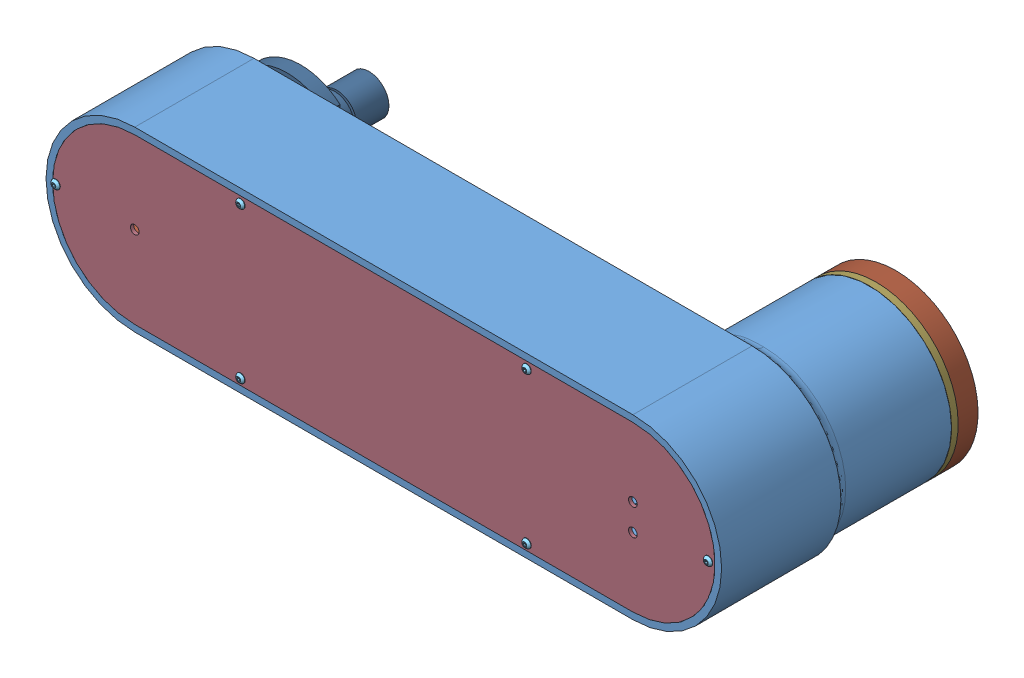
SolidWorks assembly Motor Link, configuration Default. Lengths in mm.
Overall size (327.1 91.59 127.3).
63 component instances, 27 part files, 112 mates.
Components (placement in the parent):
- Motor Link Frame-1: Motor Link Frame [Default] at (-50.4139 21.6178 -80.676) size (323.85 85.09 113.36)
- EC60 Motor-1: EC60 Motor [Default] at (-50.4139 21.6178 -74.326) x (0 0 1) z (0.889011 0.457885 0) size (61.3 68 68)
- Magnet Encoders E3-X-750-X-H-D-X-1: Magnet Encoders E3-X-750-X-H-D-X [Default] at (188.3461 21.6178 -70.897) x (0 -1 0) z (-1 0 0) size (55.98 16.26 66.52)
- EM237 Magnet-1: EM237 Magnet [Default] at (188.3461 21.6178 -135.4915) x (0.985716 -0.168418 0) z (0.168418 0.985716 0) size (60.08 25.02 60.08)
- magnet holder-1: magnet holder [Default] at (191.8291 19.6509 -122.982) x (0.870755 -0.491717 0) z (-0.491717 -0.870755 0) size (50.8 63.9 50.6)
- PCB_Battery Assembly-3: PCB_Battery Assembly [Default] at (165.0497 -0.0136 45.5715) x (1 0 0) z (0 1 0) size (117.17 24.87 77.22)
  - Battery Holder - keystone-PN1043-1: Battery Holder - keystone-PN1043 [Default] at (-125.3925 103.3982 18.9155) x (1 0 0) z (0 0 -1) size (20.65 18.93 77.14)
  - Battery PCB-1: Battery PCB [Default] at (-148.3186 115.135 -16.9005) x (1 0 0) z (0 -1 0) size (117.17 77.06 1.59)
  - battery_6612-1: battery_6612 [Default] at (-117.0385 104.4035 -11.3639) x (-0.413992 0.91028 0) z (0.91028 0.413992 0) size (18.3 65.05 18.3)
  - battery_6612-2: battery_6612 [Default] at (-137.9935 104.4035 54.6265) x (-0.916106 0.400937 0) z (-0.400937 -0.916106 0) size (18.3 65.05 18.3)
  - Battery Holder - keystone-PN1043-2: Battery Holder - keystone-PN1043 [Default] at (-129.6396 103.3982 24.3471) x (-1 0 0) z (0 0 1) size (20.65 18.93 77.14)
  - Battery Holder - keystone-PN1043-3: Battery Holder - keystone-PN1043 [Default] at (-104.4375 103.3982 18.9155) x (1 0 0) z (0 0 -1) size (20.65 18.93 77.14)
  - battery_6612-3: battery_6612 [Default] at (-96.0835 104.4035 -10.3735) x (1 0 0) z (0 -1 0) size (18.3 65.05 18.3)
  - Battery Holder - keystone-PN1043-4: Battery Holder - keystone-PN1043 [Default] at (-83.4825 103.3982 18.9155) x (1 0 0) z (0 0 -1) size (20.65 18.93 77.14)
  - Battery Holder - keystone-PN1043-5: Battery Holder - keystone-PN1043 [Default] at (-45.8196 103.3982 24.3471) x (-1 0 0) z (0 0 1) size (20.65 18.93 77.14)
  - battery_6612-4: battery_6612 [Default] at (-75.1285 104.4035 -11.3639) x (-0.923728 -0.383049 0) z (-0.383049 0.923728 0) size (18.3 65.05 18.3)
  - battery_6612-5: battery_6612 [Default] at (-54.1735 104.4035 54.6265) x (-1 0 0) z (0 -1 0) size (18.3 65.05 18.3)
- carrier_shaft-1: carrier_shaft [Default] at (-50.4139 39.1178 -75.596) x (-0.887515 0.46078 0) z (-0.46078 -0.887515 0) size (9 25.81 9)
- carrier_shaft-2: carrier_shaft [Default] at (-50.4139 4.1178 -75.596) x (-0.791269 0.611469 0) z (-0.611469 -0.791269 0) size (9 25.81 9)
- Shaft_Carrier_Combined-1: Shaft_Carrier_Combined [Default] at (-50.4139 21.6178 -103.1385) x (0 1 0) z (-1 0 0) size (57.15 55.17 57.15)
- Delrin_Ring-1: Delrin_Ring [Default] at (188.3461 21.6178 -149.5885) x (1 0 0) z (0 -1 0) size (78.74 9.53 78.74)
- Neoprene Ring-1: Neoprene Ring [Default] at (188.3461 21.6178 -140.0635) x (1 0 0) z (0 -1 0) size (78.74 3.17 78.74)
- Motor Link Acrylic Cover-1: Motor Link Acrylic Cover [Default] at (188.3461 21.6178 -25.1135) x (-1 0 0) z (0 1 0) size (317.5 1.59 78.74) (hidden)
- Slip Ring M322M1-0600-1: Slip Ring M322M1-0600 [Default] at (188.3461 21.6178 -50.305) x (-0.866025 -0.5 0) z (0 0 -1) size (44 44 48)
- bearing_8mmID_mcmaster_7804K115-1: bearing_8mmID_mcmaster_7804K115 [7804K115] at (-50.4139 39.1178 -78.926) x (-0.923728 -0.383049 0) z (0 0 -1) size (12 12 3.5)
- bearing_8mmID_mcmaster_7804K115-2: bearing_8mmID_mcmaster_7804K115 [7804K115] at (-50.4139 4.1178 -78.926) x (0.919429 -0.393256 0) z (0 0 -1) size (12 12 3.5)
- Bearing-I8mmO16mm-1: Bearing-I8mmO16mm [7804K117] at (-50.4139 4.1178 -99.051) x (0.999987 0.005155 0) z (0 0 1) size (16 16 5)
- Bearing-I8mmO16mm-2: Bearing-I8mmO16mm [7804K117] at (-50.4139 39.1178 -99.051) x (0.862389 -0.506247 0) z (0 0 -1) size (16 16 5)
- Bearing - .750-1: Bearing - .750 [3760T241] at (188.3461 21.6178 -86.2323) x (-0.324728 0.945808 0) z (0 0 1) size (41.27 41.27 11.11)
- Bearing - .750-2: Bearing - .750 [3760T241] at (188.3461 21.6178 -97.3448) x (0.923728 0.383049 0) z (0 0 -1) size (41.27 41.27 11.11)
- 10-32 Button Cap Thread Locking Screw-1: 10-32 Button Cap Thread Locking Screw [92360A244] at (-26.9189 13.9978 -89.5914) x (-0.890787 -0.45442 0) z (0 0 -1) size (9.17 9.17 12.51)
- 10-32 Button Cap Thread Locking Screw-2: 10-32 Button Cap Thread Locking Screw [92360A244] at (-73.9089 13.9978 -89.5914) x (-0.923728 -0.383049 0) z (0 0 -1) size (9.17 9.17 12.51)
- 10-32 Button Cap Thread Locking Screw-3: 10-32 Button Cap Thread Locking Screw [92360A244] at (-26.9189 29.2378 -89.5914) x (-0.923728 -0.383049 0) z (0 0 -1) size (9.17 9.17 12.51)
- 10-32 Button Cap Thread Locking Screw-4: 10-32 Button Cap Thread Locking Screw [92360A244] at (-73.9089 29.2378 -89.5914) x (-0.923728 -0.383049 0) z (0 0 -1) size (9.17 9.17 12.51)
- 1.625 Bore Internal Retaining Ring-1: 1.625 Bore Internal Retaining Ring [99142A560] at (188.3461 21.6178 -103.0534) x (1 0 0) z (0 -1 0) size (45.82 1.57 43.68)
- M8_L16mm Screws-1: M8_L16mm Screws [91760A423] at (188.3461 21.6178 -132.632) x (0.923728 0.383049 0) z (0 0 -1) size (13 13 24.67)
- .75 Bore External Retaining Ring-1: .75 Bore External Retaining Ring [97633A250] at (188.3461 21.6178 -80.1426) x (0 0 1) z (0.923728 0.383049 0) size (1.07 23.39 21.18)
- Dowel Pin - .0625-1: Dowel Pin - .0625 [97395A414] at (188.3461 57.8128 -133.7135) x (0 0 1) z (-1 0 0) size (19.05 1.59 1.59)
- Dowel Pin - .0625-2: Dowel Pin - .0625 [97395A414] at (224.5411 21.6178 -133.7135) x (0 0 1) z (-1 0 0) size (19.05 1.59 1.59)
- Dowel Pin - .0625-3: Dowel Pin - .0625 [97395A414] at (188.3461 -14.5772 -133.7135) x (0 0 1) z (-1 0 0) size (19.05 1.59 1.59)
- Dowel Pin - .0625-4: Dowel Pin - .0625 [97395A414] at (152.1511 21.6178 -133.7135) x (0 0 1) z (-1 0 0) size (19.05 1.59 1.59)
- 2-56 Screw-1: 2-56 Screw [98164A427] at (-88.1964 21.6178 -22.3576) size (4.17 4.17 10.95)
- 2-56 Screw-2: 2-56 Screw [98164A427] at (0.3861 57.8128 -22.3576) x (0.033268 -0.999446 0) z (0 0 1) size (4.17 4.17 10.95)
- 2-56 Screw-3: 2-56 Screw [98164A427] at (0.3861 -14.5772 -22.3576) size (4.17 4.17 10.95)
- 2-56 Screw-4: 2-56 Screw [98164A427] at (137.5461 -14.5772 -22.3576) size (4.17 4.17 10.95)
- 2-56 Screw-5: 2-56 Screw [98164A427] at (224.5411 21.6178 -22.3576) size (4.17 4.17 10.95)
- 2-56 Screw-6: 2-56 Screw [98164A427] at (137.5461 57.8128 -22.3576) size (4.17 4.17 10.95)
- M5 Screws-1: M5 Screws [91352A131] at (197.0961 36.7732 -47.555) size (9.5 9.5 13.21)
- M5 Screws-2: M5 Screws [91352A131] at (197.0961 6.4623 -47.555) size (9.5 9.5 13.21)
- M5 Screws-3: M5 Screws [91352A131] at (170.8461 21.6178 -47.555) size (9.5 9.5 13.21)
- M5 Nylon Spacer-1: M5 Nylon Spacer [93657A042] at (198.7861 21.6178 -55.705) size (8 8 6)
- M5 Nylon Spacer-2: M5 Nylon Spacer [93657A042] at (197.0961 6.4623 -55.705) x (-0.923728 -0.383049 0) z (0 0 -1) size (8 8 6)
- M5 Nylon Spacer-3: M5 Nylon Spacer [93657A042] at (197.0961 36.7732 -55.705) size (8 8 6)
- 4-40 Screws-1: 4-40 Screws [92949A108] at (188.3461 -1.3946 -69.3984) size (5.41 5.41 11.35)
- 4-40 Screws-2: 4-40 Screws [92949A108] at (188.3461 44.6302 -69.3984) size (5.41 5.41 11.35)
- 2-56 Screw-7: 2-56 Screw [98164A427] at (13.556 53.7996 -66.8076) size (4.17 4.17 10.95)
- 2-56 Screw-8: 2-56 Screw [98164A427] at (124.3762 53.7996 -66.8076) size (4.17 4.17 10.95)
- 2-56 Screw-9: 2-56 Screw [98164A427] at (124.3762 -10.564 -66.8076) size (4.17 4.17 10.95)
- 2-56 Screw-10: 2-56 Screw [98164A427] at (13.556 -10.564 -66.8076) size (4.17 4.17 10.95)
- #2 Spacer-1: #2 Spacer [94639A188] at (13.556 -10.564 -71.9448) x (0.923728 0.383049 0) z (0 0 -1) size (6.35 6.35 4.76)
- #2 Spacer-2: #2 Spacer [94639A188] at (124.3762 -10.564 -71.9448) x (0.923728 0.383049 0) z (0 0 -1) size (6.35 6.35 4.76)
- #2 Spacer-3: #2 Spacer [94639A188] at (124.3762 53.7996 -71.9448) x (0.923728 0.383049 0) z (0 0 -1) size (6.35 6.35 4.76)
- #2 Spacer-4: #2 Spacer [94639A188] at (13.556 53.7996 -71.9448) x (0.923728 0.383049 0) z (0 0 -1) size (6.35 6.35 4.76)
Mates (geometry in assembly coordinates):
- Coincident2: coincident aligned: line of Motor Link Frame-1 through (-50.4139 21.6178 -80.676) axis (0 0 1); line of EC60 Motor-1 through (-50.4139 21.6178 -95.9581) axis (0 0 1)
- Coincident3: coincident anti-aligned: plane of Motor Link Frame-1 through (-50.4139 21.6178 -74.326) normal (0 0 1); plane of EC60 Motor-1
- Coincident4: coincident: plane of Motor Link Frame-1 through (-50.4139 21.6178 -80.676) normal (0 0 -1); plane of bearing_8mmID_mcmaster_7804K115-1 through (-50.4139 39.1178 -80.676) normal (0 0 -1)
- Coincident5: coincident aligned: line of Motor Link Frame-1 through (-50.4139 39.1178 -80.676) axis (0 0 1); line of bearing_8mmID_mcmaster_7804K115-1 through (-50.4139 39.1178 -77.176) axis (0 0 1)
- Coincident6: coincident: plane of Motor Link Frame-1 through (-50.4139 21.6178 -80.676) normal (0 0 -1); plane of bearing_8mmID_mcmaster_7804K115-2 through (-50.4139 4.1178 -80.676) normal (0 0 -1)
- Coincident7: coincident aligned: line of Motor Link Frame-1 through (-50.4139 4.1178 -80.676) axis (0 0 1); line of bearing_8mmID_mcmaster_7804K115-2 through (-50.4139 4.1178 -77.176) axis (0 0 1)
- Concentric1: concentric: point of Motor Link Frame-1; cylinder of Magnet Encoders E3-X-750-X-H-D-X-1 through (188.3461 21.6178 -64.3438) axis (0 0 1) radius 9.5263
- Coincident11: coincident anti-aligned: plane of Motor Link Frame-1 through (-50.4139 21.6178 -74.326) normal (0 0 1); plane of Magnet Encoders E3-X-750-X-H-D-X-1 through (188.3461 21.6178 -74.326) normal (0 0 -1)
- Perpendicular1: perpendicular: plane of Motor Link Frame-1 through (-50.4139 64.1628 -80.676) normal (0 1 0); plane of Magnet Encoders E3-X-750-X-H-D-X-1 through (155.1229 6.0623 -72.4718) normal (-0.999391 0 0.034899)
- Concentric2: concentric aligned: line of Motor Link Frame-1 through (188.3461 21.6178 -136.8885) axis (0 0 1); cylinder of EM237 Magnet-1 through (188.3461 21.6178 -148.001) axis (0 0 1) radius 30.0419
- Coincident16: coincident anti-aligned: line of Motor Link Frame-1 through (188.3461 21.6178 -136.8885) axis (0 0 1); line of magnet holder-1 through (188.3461 21.6178 -59.086) axis (0 0 -1)
- Coincident26: coincident aligned: line of carrier_shaft-1 through (-50.4139 39.1178 -92.596) axis (0 0 1); line of Motor Link Frame-1 through (-50.4139 39.1178 -80.676) axis (0 0 1)
- Coincident29: coincident aligned: line of Motor Link Frame-1 through (-50.4139 4.1178 -80.676) axis (0 0 1); line of carrier_shaft-2 through (-50.4139 4.1178 -92.596) axis (0 0 1)
- Coincident37: coincident aligned: line of Motor Link Frame-1 through (-50.4139 21.6178 -80.676) axis (0 0 1); line of Shaft_Carrier_Combined-1 through (-50.4139 21.6178 -135.841) axis (0 0 1)
- Coincident38: coincident aligned: line of Motor Link Frame-1 through (-50.4139 4.1178 -80.676) axis (0 0 1); line of Shaft_Carrier_Combined-1 through (-50.4139 4.1178 -101.551) axis (0 0 1)
- Coincident39: coincident aligned: line of Motor Link Frame-1 through (-50.4139 39.1178 -80.676) axis (0 0 1); line of Shaft_Carrier_Combined-1 through (-50.4139 39.1178 -101.551) axis (0 0 1)
- Coincident41: coincident anti-aligned: plane of Motor Link Frame-1 through (-50.4139 21.6178 -80.676) normal (0 0 -1); plane of Shaft_Carrier_Combined-1
- Coincident42: coincident anti-aligned: line of Shaft_Carrier_Combined-1 through (-50.4139 4.1178 -101.551) axis (0 0 1); line of Bearing-I8mmO16mm-1 through (-50.4139 4.1178 -101.551) axis (0 0 -1)
- Coincident44: coincident aligned: line of Shaft_Carrier_Combined-1 through (-50.4139 39.1178 -101.551) axis (0 0 1); line of Bearing-I8mmO16mm-2 through (-50.4139 39.1178 -96.551) axis (0 0 1)
- Coincident46: coincident anti-aligned: plane of Motor Link Frame-1 through (-50.4139 39.1178 -75.596) normal (0 0 -1); plane of carrier_shaft-1 through (-50.4139 39.1178 -75.596) normal (0 0 1)
- Coincident47: coincident anti-aligned: plane of Motor Link Frame-1 through (-50.4139 4.1178 -75.596) normal (0 0 -1); plane of carrier_shaft-2 through (-50.4139 4.1178 -75.596) normal (0 0 1)
- Coincident51: coincident anti-aligned: plane of Shaft_Carrier_Combined-1 through (-50.4139 4.1178 -101.551) normal (0 0 1); plane of Bearing-I8mmO16mm-1 through (-50.4538 11.8676 -101.551) normal (0 0 -1)
- Coincident52: coincident anti-aligned: plane of Shaft_Carrier_Combined-1 through (-50.4139 39.1178 -101.551) normal (0 0 1); plane of Bearing-I8mmO16mm-2 through (-54.3373 32.4342 -101.551) normal (0 0 -1)
- Coincident53: coincident aligned: line of Motor Link Frame-1 through (-26.9189 13.9978 -76.866) axis (0 0 -1); line of 10-32 Button Cap Thread Locking Screw-1 through (-26.9189 13.9978 -77.501) axis (0 0 -1)
- Coincident54: coincident anti-aligned: plane of Shaft_Carrier_Combined-1 through (-50.4139 21.6178 -87.026) normal (0 0 -1); plane of 10-32 Button Cap Thread Locking Screw-1 through (-24.8355 9.9138 -87.026) normal (0 0 1)
- Coincident55: coincident anti-aligned: plane of Shaft_Carrier_Combined-1 through (-50.4139 21.6178 -87.026) normal (0 0 -1); plane of 10-32 Button Cap Thread Locking Screw-3 through (-25.1627 25.0027 -87.026) normal (0 0 1)
- Coincident56: coincident aligned: line of Motor Link Frame-1 through (-26.9189 29.2378 -76.866) axis (0 0 -1); line of 10-32 Button Cap Thread Locking Screw-3 through (-26.9189 29.2378 -77.501) axis (0 0 -1)
- Coincident57: coincident aligned: line of Motor Link Frame-1 through (-73.9089 13.9978 -76.866) axis (0 0 -1); line of 10-32 Button Cap Thread Locking Screw-2 through (-73.9089 13.9978 -77.501) axis (0 0 -1)
- Coincident58: coincident anti-aligned: plane of Shaft_Carrier_Combined-1 through (-50.4139 21.6178 -87.026) normal (0 0 -1); plane of 10-32 Button Cap Thread Locking Screw-2 through (-72.1527 9.7627 -87.026) normal (0 0 1)
- Coincident59: coincident aligned: line of Motor Link Frame-1 through (-73.9089 29.2378 -76.866) axis (0 0 -1); line of 10-32 Button Cap Thread Locking Screw-4 through (-73.9089 29.2378 -77.501) axis (0 0 -1)
- Coincident60: coincident anti-aligned: plane of Shaft_Carrier_Combined-1 through (-50.4139 21.6178 -87.026) normal (0 0 -1); plane of 10-32 Button Cap Thread Locking Screw-4 through (-72.1527 25.0027 -87.026) normal (0 0 1)
- Coincident61: coincident anti-aligned: line of Motor Link Frame-1 through (188.3461 21.6178 -136.8885) axis (0 0 1); line of Bearing - .750-1 through (188.3461 21.6178 -91.7885) axis (0 0 -1)
- Coincident62: coincident anti-aligned: plane of Motor Link Frame-1 through (188.3461 21.6178 -80.676) normal (0 0 -1); plane of Bearing - .750-1 through (169.3525 15.0966 -80.676) normal (0 0 1)
- Concentric6: concentric aligned: line of Motor Link Frame-1 through (188.3461 21.6178 -136.8885) axis (0 0 1); cylinder of 1.625 Bore Internal Retaining Ring-1 through (188.3461 21.6178 -104.6282) axis (0 0 1) radius 22.9108
- Concentric8: concentric anti-aligned: line of Motor Link Frame-1 through (188.3461 21.6178 -136.8885) axis (0 0 1); cylinder of Bearing - .750-2 through (188.3461 21.6178 -102.901) axis (0 0 -1) radius 9.525
- Coincident68: coincident anti-aligned: plane of Motor Link Frame-1 through (188.3461 21.6178 -104.6282) normal (0 0 1); plane of 1.625 Bore Internal Retaining Ring-1 through (199.3349 4.8737 -104.6282) normal (0 0 -1)
- Coincident69: coincident anti-aligned: plane of Bearing - .750-1 through (169.3525 15.0966 -91.7885) normal (0 0 -1); plane of Bearing - .750-2 through (196.0385 3.0676 -91.7885) normal (0 0 1)
- Coincident71: coincident anti-aligned: plane of magnet holder-1 through (199.4047 15.3729 -102.901) normal (0 0 1); plane of Bearing - .750-2 through (193.6151 8.9115 -102.901) normal (0 0 -1)
- Coincident72: coincident anti-aligned: plane of EM237 Magnet-1 through (188.3461 21.6178 -122.982) normal (0 0 1); plane of magnet holder-1 through (191.8291 19.6509 -122.982) normal (0 0 -1)
- Concentric9: concentric aligned: line of magnet holder-1 through (188.3461 21.6178 -59.086) axis (0 0 -1); cylinder of M8_L16mm Screws-1 through (188.3461 21.6178 -108.632) axis (0 0 -1) radius 6.5
- Coincident74: coincident anti-aligned: plane of magnet holder-1 through (194.221 18.3002 -116.632) normal (0 0 1); plane of M8_L16mm Screws-1 through (188.3461 21.6178 -116.632) normal (0 0 -1)
- Concentric10: concentric aligned: line of magnet holder-1 through (188.3461 21.6178 -59.086) axis (0 0 -1); cylinder of .75 Bore External Retaining Ring-1 through (188.3461 21.6178 -79.6092) axis (0 0 -1) radius 8.8011
- Coincident77: coincident anti-aligned: plane of magnet holder-1 through (188.3461 21.6178 -80.676) normal (0 0 1); plane of .75 Bore External Retaining Ring-1 through (188.3461 21.6178 -80.676) normal (0 0 -1)
- Coincident78: coincident anti-aligned: plane of Motor Link Frame-1 through (188.3461 21.6178 -136.8885) normal (0 0 -1); plane of Neoprene Ring-1 through (188.3461 21.6178 -136.8885) normal (0 0 1)
- Concentric11: concentric anti-aligned: line of Motor Link Frame-1 through (188.3461 21.6178 -136.8885) axis (0 0 1); cylinder of Neoprene Ring-1 through (188.3461 21.6178 -136.8885) axis (0 0 -1) radius 33.02
- Concentric12: concentric anti-aligned: line of Motor Link Frame-1 through (188.3461 21.6178 -136.8885) axis (0 0 1); cylinder of Delrin_Ring-1 through (188.3461 21.6178 -140.0635) axis (0 0 -1) radius 33.02
- Coincident81: coincident anti-aligned: plane of Delrin_Ring-1 through (188.3461 21.6178 -140.0635) normal (0 0 1); plane of Neoprene Ring-1 through (188.3461 21.6178 -140.0635) normal (0 0 -1)
- Concentric13: concentric aligned: cylinder of Motor Link Frame-1 through (224.5411 21.6178 -124.1885) axis (0 0 -1) radius 0.7937; cylinder of Neoprene Ring-1 through (224.5411 21.6178 -136.8885) axis (0 0 -1) radius 0.7937
- Concentric14: concentric aligned: cylinder of Motor Link Frame-1 through (224.5411 21.6178 -124.1885) axis (0 0 -1) radius 0.7937; cylinder of Delrin_Ring-1 through (224.5411 21.6178 -140.0635) axis (0 0 -1) radius 0.7937
- Concentric15: concentric anti-aligned: cylinder of Motor Link Frame-1 through (224.5411 21.6178 -124.1885) axis (0 0 -1) radius 0.7937; cylinder of Dowel Pin - .0625-2 through (224.5411 21.6178 -143.2385) axis (0 0 1) radius 0.7937
- Coincident82: coincident anti-aligned: plane of Motor Link Frame-1 through (224.5411 21.6178 -124.1885) normal (0 0 -1); plane of Dowel Pin - .0625-2 through (224.5411 21.6178 -124.1885) normal (0 0 1)
- Concentric16: concentric anti-aligned: cylinder of Motor Link Frame-1 through (188.3461 57.8128 -124.1885) axis (0 0 -1) radius 0.7937; cylinder of Dowel Pin - .0625-1 through (188.3461 57.8128 -143.2385) axis (0 0 1) radius 0.7937
- Coincident83: coincident anti-aligned: plane of Motor Link Frame-1 through (188.3461 57.8128 -124.1885) normal (0 0 -1); plane of Dowel Pin - .0625-1 through (188.3461 57.8128 -124.1885) normal (0 0 1)
- Concentric17: concentric anti-aligned: cylinder of Motor Link Frame-1 through (152.1511 21.6178 -124.1885) axis (0 0 -1) radius 0.7937; cylinder of Dowel Pin - .0625-4 through (152.1511 21.6178 -143.2385) axis (0 0 1) radius 0.7937
- Coincident84: coincident anti-aligned: plane of Motor Link Frame-1 through (152.1511 21.6178 -124.1885) normal (0 0 -1); plane of Dowel Pin - .0625-4 through (152.1511 21.6178 -124.1885) normal (0 0 1)
- Concentric18: concentric anti-aligned: cylinder of Motor Link Frame-1 through (188.3461 -14.5772 -124.1885) axis (0 0 -1) radius 0.7937; cylinder of Dowel Pin - .0625-3 through (188.3461 -14.5772 -143.2385) axis (0 0 1) radius 0.7937
- Coincident85: coincident anti-aligned: plane of Motor Link Frame-1 through (188.3461 -14.5772 -124.1885) normal (0 0 -1); plane of Dowel Pin - .0625-3 through (188.3461 -14.5772 -124.1885) normal (0 0 1)
- Coincident86: coincident anti-aligned: plane of Motor Link Acrylic Cover-1 through (188.3461 21.6178 -25.1135) normal (0 0 -1); plane of Motor Link Frame-1 through (-50.4139 21.6178 -25.1135) normal (0 0 1)
- Concentric26: concentric anti-aligned: cylinder of Motor Link Frame-1 through (-88.1964 21.6178 -25.1135) axis (0 0 1) radius 0.889; cylinder of Motor Link Acrylic Cover-1 through (-88.1964 21.6178 -23.526) axis (0 0 -1) radius 1.0922
- Concentric27: concentric anti-aligned: cylinder of Motor Link Frame-1 through (224.5411 21.6178 -25.1135) axis (0 0 1) radius 0.889; cylinder of Motor Link Acrylic Cover-1 through (224.5411 21.6178 -23.526) axis (0 0 -1) radius 1.0922
- Concentric28: concentric anti-aligned: cylinder of Motor Link Acrylic Cover-1 through (-88.1964 21.6178 -23.526) axis (0 0 -1) radius 1.0922; line of 2-56 Screw-1 through (-88.1964 21.6178 -33.051) axis (0 0 1)
- Coincident88: coincident anti-aligned: plane of Motor Link Acrylic Cover-1 through (188.3461 21.6178 -23.526) normal (0 0 1); plane of 2-56 Screw-1 through (-88.1964 19.535 -23.526) normal (0 0 -1)
- Concentric29: concentric anti-aligned: cylinder of Motor Link Acrylic Cover-1 through (0.3861 57.8128 -23.526) axis (0 0 -1) radius 1.0922; line of 2-56 Screw-2 through (0.3861 57.8128 -33.051) axis (0 0 1)
- Coincident90: coincident anti-aligned: plane of Motor Link Acrylic Cover-1 through (188.3461 21.6178 -23.526) normal (0 0 1); plane of 2-56 Screw-2 through (-1.6955 57.7435 -23.526) normal (0 0 -1)
- Concentric30: concentric anti-aligned: cylinder of Motor Link Acrylic Cover-1 through (0.3861 -14.5772 -23.526) axis (0 0 -1) radius 1.0922; line of 2-56 Screw-3 through (0.3861 -14.5772 -33.051) axis (0 0 1)
- Coincident92: coincident anti-aligned: plane of Motor Link Acrylic Cover-1 through (188.3461 21.6178 -23.526) normal (0 0 1); plane of 2-56 Screw-3 through (0.3861 -16.66 -23.526) normal (0 0 -1)
- Concentric31: concentric anti-aligned: cylinder of Motor Link Acrylic Cover-1 through (137.5461 -14.5772 -23.526) axis (0 0 -1) radius 1.0922; line of 2-56 Screw-4 through (137.5461 -14.5772 -33.051) axis (0 0 1)
- Coincident94: coincident anti-aligned: plane of Motor Link Acrylic Cover-1 through (188.3461 21.6178 -23.526) normal (0 0 1); plane of 2-56 Screw-4 through (137.5461 -16.66 -23.526) normal (0 0 -1)
- Concentric32: concentric anti-aligned: cylinder of Motor Link Acrylic Cover-1 through (137.5461 57.8128 -23.526) axis (0 0 -1) radius 1.0922; line of 2-56 Screw-6 through (137.5461 57.8128 -33.051) axis (0 0 1)
- Coincident96: coincident anti-aligned: plane of Motor Link Acrylic Cover-1 through (188.3461 21.6178 -23.526) normal (0 0 1); plane of 2-56 Screw-6 through (137.5461 55.73 -23.526) normal (0 0 -1)
- Concentric33: concentric anti-aligned: cylinder of Motor Link Acrylic Cover-1 through (224.5411 21.6178 -23.526) axis (0 0 -1) radius 1.0922; line of 2-56 Screw-5 through (224.5411 21.6178 -33.051) axis (0 0 1)
- Coincident98: coincident anti-aligned: plane of Motor Link Acrylic Cover-1 through (188.3461 21.6178 -23.526) normal (0 0 1); plane of 2-56 Screw-5 through (224.5411 19.535 -23.526) normal (0 0 -1)
- Distance2: distance = 6 mm anti-aligned: plane of Slip Ring M322M1-0600-1 through (169.2936 10.6178 -52.705) normal (0 0 -1); plane of Magnet Encoders E3-X-750-X-H-D-X-1 through (188.3461 21.6178 -58.705) normal (0 0 1)
- Concentric34: concentric aligned: line of Motor Link Frame-1 through (188.3461 21.6178 -136.8885) axis (0 0 1); cylinder of Slip Ring M322M1-0600-1 through (188.3461 21.6178 -66.705) axis (0 0 1) radius 3.8
- Concentric35: concentric aligned: cylinder of Slip Ring M322M1-0600-1 through (170.8461 21.6178 -50.305) axis (0 0 1) radius 2.75; cylinder of Magnet Encoders E3-X-750-X-H-D-X-1 through (170.8461 21.6178 -58.705) axis (0 0 1) radius 2.1
- Concentric36: concentric aligned: cylinder of Magnet Encoders E3-X-750-X-H-D-X-1 through (197.0961 6.4623 -58.705) axis (0 0 1) radius 2.1; cylinder of Slip Ring M322M1-0600-1 through (197.0961 6.4623 -50.305) axis (0 0 1) radius 2.75
- Concentric37: concentric aligned: cylinder of Magnet Encoders E3-X-750-X-H-D-X-1 through (197.0961 36.7732 -58.705) axis (0 0 1) radius 2.1; cylinder of Slip Ring M322M1-0600-1 through (197.0961 36.7732 -50.305) axis (0 0 1) radius 2.75
- Concentric38: concentric aligned: cylinder of Slip Ring M322M1-0600-1 through (197.0961 36.7732 -50.305) axis (0 0 1) radius 2.75; line of M5 Screws-1 through (197.0961 36.7732 -60.305) axis (0 0 1)
- Coincident102: coincident anti-aligned: plane of Slip Ring M322M1-0600-1 through (188.3461 21.6178 -50.305) normal (0 0 1); plane of M5 Screws-1 through (197.0961 32.0232 -50.305) normal (0 0 -1)
- Concentric39: concentric aligned: cylinder of Slip Ring M322M1-0600-1 through (197.0961 6.4623 -50.305) axis (0 0 1) radius 2.75; line of M5 Screws-2 through (197.0961 6.4623 -60.305) axis (0 0 1)
- Coincident104: coincident anti-aligned: plane of Slip Ring M322M1-0600-1 through (188.3461 21.6178 -50.305) normal (0 0 1); plane of M5 Screws-2 through (197.0961 1.7123 -50.305) normal (0 0 -1)
- Concentric40: concentric aligned: cylinder of Slip Ring M322M1-0600-1 through (170.8461 21.6178 -50.305) axis (0 0 1) radius 2.75; line of M5 Screws-3 through (170.8461 21.6178 -60.305) axis (0 0 1)
- Coincident106: coincident anti-aligned: plane of Slip Ring M322M1-0600-1 through (188.3461 21.6178 -50.305) normal (0 0 1); plane of M5 Screws-3 through (170.8461 16.8678 -50.305) normal (0 0 -1)
- Coincident107: coincident anti-aligned: plane of Magnet Encoders E3-X-750-X-H-D-X-1 through (188.3461 21.6178 -58.705) normal (0 0 1); plane of M5 Nylon Spacer-1 through (198.7861 21.6178 -58.705) normal (0 0 -1)
- Concentric42: concentric aligned: cylinder of Slip Ring M322M1-0600-1 through (197.0961 6.4623 -50.305) axis (0 0 1) radius 2.75; cylinder of M5 Nylon Spacer-2 through (197.0961 6.4623 -58.705) axis (0 0 1) radius 2.65
- Coincident108: coincident anti-aligned: plane of Magnet Encoders E3-X-750-X-H-D-X-1 through (188.3461 21.6178 -58.705) normal (0 0 1); plane of M5 Nylon Spacer-2 through (197.0961 6.4623 -58.705) normal (0 0 -1)
- Concentric43: concentric anti-aligned: cylinder of Slip Ring M322M1-0600-1 through (197.0961 36.7732 -50.305) axis (0 0 1) radius 2.75; cylinder of M5 Nylon Spacer-3 through (197.0961 36.7732 -52.705) axis (0 0 -1) radius 2.65
- Coincident109: coincident anti-aligned: plane of Slip Ring M322M1-0600-1 through (169.2936 10.6178 -52.705) normal (0 0 -1); plane of M5 Nylon Spacer-3 through (197.0961 36.7732 -52.705) normal (0 0 1)
- Concentric48: concentric: cylinder of Motor Link Frame-1 through (-71.9139 21.6178 -80.676) axis (0 0 -1) radius 4; cylinder of EC60 Motor-1 through (-71.9139 21.6178 -74.326) axis (0 0 -1) radius 1.65
- Concentric49: concentric anti-aligned: cylinder of Magnet Encoders E3-X-750-X-H-D-X-1 through (188.3461 -1.3946 -70.897) axis (0 0 -1) radius 1.4351; line of 4-40 Screws-1 through (188.3461 -1.3946 -80.422) axis (0 0 1)
- Coincident115: coincident anti-aligned: plane of Magnet Encoders E3-X-750-X-H-D-X-1 through (188.3461 21.6178 -70.897) normal (0 0 1); plane of 4-40 Screws-1 through (188.3461 -4.0997 -70.897) normal (0 0 -1)
- Concentric50: concentric anti-aligned: cylinder of Magnet Encoders E3-X-750-X-H-D-X-1 through (188.3461 44.6302 -70.897) axis (0 0 -1) radius 1.4351; line of 4-40 Screws-2 through (188.3461 44.6302 -80.422) axis (0 0 1)
- Coincident117: coincident anti-aligned: plane of Magnet Encoders E3-X-750-X-H-D-X-1 through (188.3461 21.6178 -70.897) normal (0 0 1); plane of 4-40 Screws-2 through (188.3461 41.9251 -70.897) normal (0 0 -1)
- Concentric51: concentric anti-aligned: cylinder of PCB_Battery Assembly-3/Battery PCB-1 through (13.556 53.7996 -67.976) axis (0 0 -1) radius 1.0922; cylinder of 2-56 Screw-7 through (13.556 53.7996 -66.8076) axis (0 0 1) radius 2.0828
- Coincident118: coincident anti-aligned: plane of PCB_Battery Assembly-3/Battery PCB-1 through (16.731 -16.914 -67.976) normal (0 0 1); plane of 2-56 Screw-7 through (13.556 51.7168 -67.976) normal (0 0 -1)
- Concentric52: concentric anti-aligned: cylinder of PCB_Battery Assembly-3/Battery PCB-1 through (13.556 -10.564 -67.976) axis (0 0 -1) radius 1.0922; cylinder of 2-56 Screw-10 through (13.556 -10.564 -66.8076) axis (0 0 1) radius 2.0828
- Coincident119: coincident anti-aligned: plane of PCB_Battery Assembly-3/Battery PCB-1 through (16.731 -16.914 -67.976) normal (0 0 1); plane of 2-56 Screw-10 through (13.556 -12.6468 -67.976) normal (0 0 -1)
- Concentric53: concentric anti-aligned: cylinder of PCB_Battery Assembly-3/Battery PCB-1 through (124.3762 53.7996 -67.976) axis (0 0 -1) radius 1.0922; cylinder of 2-56 Screw-8 through (124.3762 53.7996 -66.8076) axis (0 0 1) radius 2.0828
- Coincident120: coincident anti-aligned: plane of PCB_Battery Assembly-3/Battery PCB-1 through (16.731 -16.914 -67.976) normal (0 0 1); plane of 2-56 Screw-8 through (124.3762 51.7168 -67.976) normal (0 0 -1)
- Coincident121: coincident anti-aligned: plane of PCB_Battery Assembly-3/Battery PCB-1 through (16.731 -16.914 -67.976) normal (0 0 1); plane of 2-56 Screw-9 through (124.3762 -12.6468 -67.976) normal (0 0 -1)
- Concentric54: concentric anti-aligned: cylinder of PCB_Battery Assembly-3/Battery PCB-1 through (124.3762 -10.564 -67.976) axis (0 0 -1) radius 1.0922; cylinder of 2-56 Screw-9 through (124.3762 -10.564 -66.8076) axis (0 0 1) radius 2.0828
- Concentric55: concentric aligned: cylinder of Motor Link Frame-1 through (124.3762 -10.564 -74.326) axis (0 0 1) radius 0.889; cylinder of #2 Spacer-2 through (124.3762 -10.564 -74.326) axis (0 0 1) radius 1.143
- Coincident122: coincident anti-aligned: plane of Motor Link Frame-1 through (-50.4139 21.6178 -74.326) normal (0 0 1); plane of #2 Spacer-2 through (124.3762 -10.564 -74.326) normal (0 0 -1)
- Concentric56: concentric aligned: cylinder of Motor Link Frame-1 through (124.3762 53.7996 -74.326) axis (0 0 1) radius 0.889; cylinder of #2 Spacer-3 through (124.3762 53.7996 -74.326) axis (0 0 1) radius 1.143
- Coincident123: coincident anti-aligned: plane of Motor Link Frame-1 through (-50.4139 21.6178 -74.326) normal (0 0 1); plane of #2 Spacer-3 through (124.3762 53.7996 -74.326) normal (0 0 -1)
- Concentric57: concentric aligned: cylinder of Motor Link Frame-1 through (13.556 -10.564 -74.326) axis (0 0 1) radius 0.889; cylinder of #2 Spacer-1 through (13.556 -10.564 -74.326) axis (0 0 1) radius 1.143
- Coincident124: coincident anti-aligned: plane of Motor Link Frame-1 through (-50.4139 21.6178 -74.326) normal (0 0 1); plane of #2 Spacer-1 through (13.556 -10.564 -74.326) normal (0 0 -1)
- Concentric58: concentric aligned: cylinder of Motor Link Frame-1 through (13.556 53.7996 -74.326) axis (0 0 1) radius 0.889; cylinder of #2 Spacer-4 through (13.556 53.7996 -74.326) axis (0 0 1) radius 1.143
- Coincident125: coincident anti-aligned: plane of Motor Link Frame-1 through (-50.4139 21.6178 -74.326) normal (0 0 1); plane of #2 Spacer-4 through (13.556 53.7996 -74.326) normal (0 0 -1)
- Coincident126: coincident anti-aligned: plane of PCB_Battery Assembly-3/Battery PCB-1 through (16.731 -16.914 -69.5635) normal (0 0 -1); plane of #2 Spacer-1 through (13.556 -10.564 -69.5635) normal (0 0 1)
- Concentric60: concentric anti-aligned: cylinder of Motor Link Frame-1 through (13.556 53.7996 -74.326) axis (0 0 1) radius 0.889; cylinder of PCB_Battery Assembly-3/Battery PCB-1 through (13.556 53.7996 -67.976) axis (0 0 -1) radius 1.0922
- Concentric61: concentric anti-aligned: cylinder of Motor Link Frame-1 through (13.556 -10.564 -74.326) axis (0 0 1) radius 0.889; cylinder of PCB_Battery Assembly-3/Battery PCB-1 through (13.556 -10.564 -67.976) axis (0 0 -1) radius 1.0922
